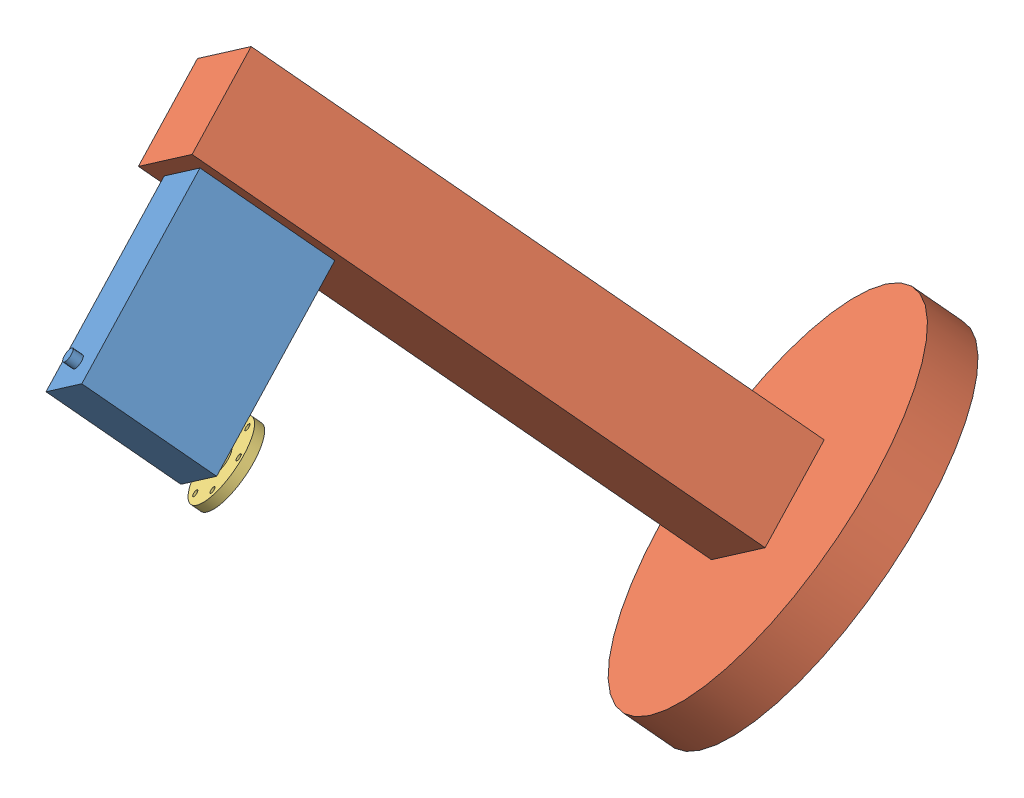
SolidWorks assembly Assem2, configuration Default. Lengths in mm.
Overall size (226.81 247.28 220.06).
3 component instances, 3 part files, 5 mates.
Components (placement in the parent):
- Part3-1: Part3 [Default] at (-65.0668 -238.1052 368.9785) x (0.189358 -0.511937 0.837893) z (0.597996 -0.616702 -0.511937) size (80 20 46)
- Practice - ERC-1: Practice - ERC [Default] at (16.1969 -324.8398 255.8488) x (0.77881 0.597996 0.189358) z (0.189358 -0.511937 0.837893) size (120 185 120)
- Practice -ERC Part 2-2: Practice -ERC Part 2 [Default] at (-51.3918 -276.6116 381.528) x (0.77881 0.597996 0.189358) z (0.189358 -0.511937 0.837893) size (25 5 25)
Mates (geometry in assembly coordinates):
- Coincident1: coincident anti-aligned: line of Practice - ERC-1 through (-96.3901 -227.4924 358.6722) axis (0.77881 0.597996 0.189358); plane of Part3-1 through (-100.1772 -217.2536 341.9143) normal (-0.597996 0.616702 0.511937)
- Coincident9: coincident anti-aligned: plane of Part3-1 through (-100.1772 -217.2536 341.9143) normal (-0.189358 0.511937 -0.837893); plane of Practice - ERC-1 through (15.2501 -322.2801 251.6593) normal (0.189358 -0.511937 0.837893)
- Coincident10: coincident anti-aligned: plane of Part3-1 through (-80.643 -250.0652 365.1913) normal (-0.77881 -0.597996 -0.189358); plane of Practice - ERC-1 through (-100.1772 -217.2536 341.9143) normal (0.77881 0.597996 0.189358)
- Concentric8: concentric aligned: cylinder of Part3-1 through (-66.6406 -260.8856 394.5824) axis (-0.597996 0.616702 0.511937) radius 2; cylinder of Practice -ERC Part 2-2 through (-49.5978 -278.4617 379.9922) axis (-0.597996 0.616702 0.511937) radius 2
- Distance4: distance = 0.5 mm anti-aligned: plane of Practice -ERC Part 2-2 through (-54.3817 -273.528 384.0877) normal (-0.597996 0.616702 0.511937); plane of Part3-1 through (-76.2574 -241.9217 321.4369) normal (0.597996 -0.616702 -0.511937)
